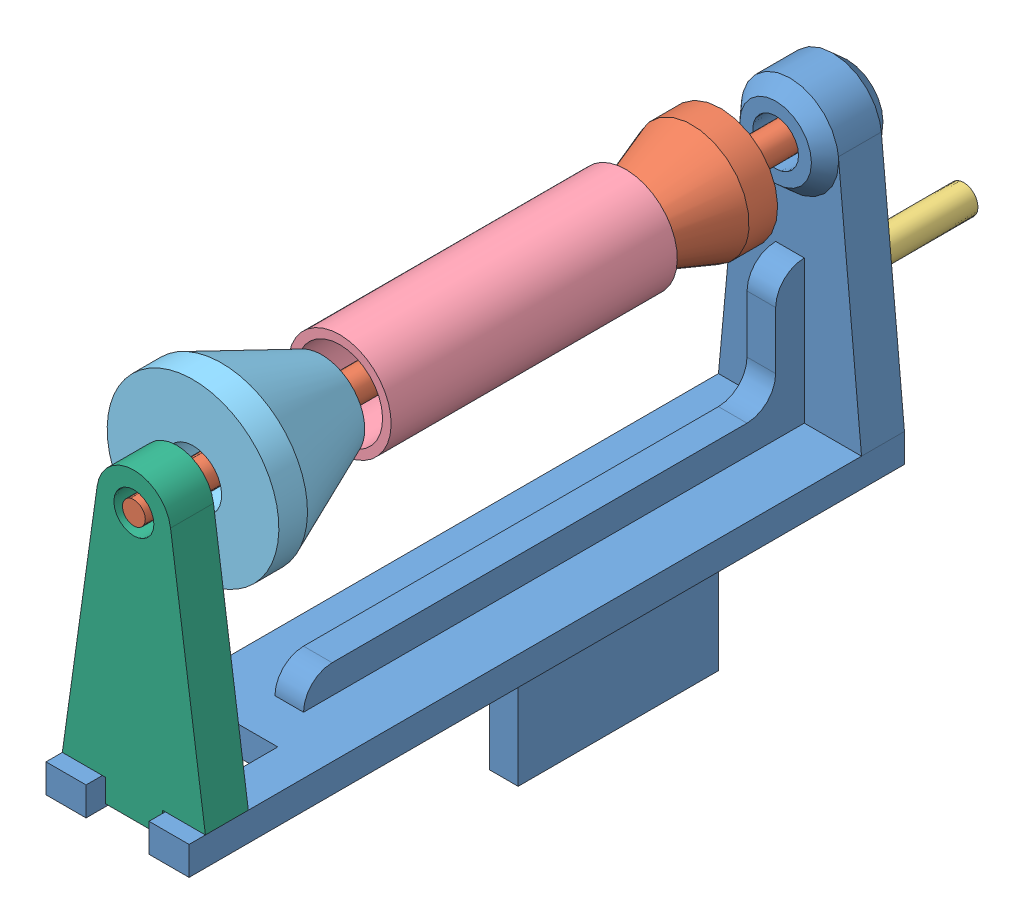
SolidWorks assembly Assem3, configuration Default. Lengths in mm.
Overall size (68.4 179.13 295.71).
6 component instances, 6 part files, 7 mates.
Components (placement in the parent):
- Part11-1: Part11 [Default] at origin size (50 161.93 255)
- spindle part-1: spindle part [Default] at (0 0 31.7929) x (0 0 -1) z (0.976249 -0.216652 0) size (250 40 40)
- spindle handle-1: spindle handle [Default] at (0 -25 -13.2071) size (18 68 47)
- coil former-1: coil former [Default] at (0 0 114.8801) x (0.979627 -0.200825 0) z (-0.200825 -0.979627 0) size (36 100 36)
- coil former locking-1: coil former locking [Default] at (0 0 193.6174) x (0 0 -1) z (0.988444 -0.151589 0) size (45 60 60)
- e nd-1: e nd [Default] at (0 0 229.2929) size (50 105.95 15)
Mates (geometry in assembly coordinates):
- Concentric2: concentric aligned: cylinder of Part11-1 through (0 0 1025) axis (0 0 1) radius 8; cylinder of spindle part-1 through (0 0 31.7929) axis (0 0 1) radius 3
- Concentric3: concentric anti-aligned: cylinder of spindle part-1 through (0 0 31.7929) axis (0 0 1) radius 3; cylinder of spindle handle-1 through (0 0 -6.2071) axis (0 0 -1) radius 3
- Coincident4: coincident aligned: plane of spindle part-1 through (0 0 -13.2071) normal (0 0 -1); plane of spindle handle-1 through (0 0 -13.2071) normal (0 0 -1)
- Concentric4: concentric anti-aligned: cylinder of spindle part-1 through (0 0 31.7929) axis (0 0 1) radius 5; cylinder of coil former-1 through (0 0 164.8801) axis (0 0 -1) radius 15
- Concentric5: concentric aligned: cylinder of spindle part-1 through (0 0 31.7929) axis (0 0 1) radius 4; cylinder of coil former locking-1 through (0 0 193.6174) axis (0 0 1) radius 10
- Concentric6: concentric anti-aligned: cylinder of spindle part-1 through (0 0 31.7929) axis (0 0 1) radius 4; cylinder of e nd-1 through (0 0 236.7929) axis (0 0 -1) radius 7
- Coincident9: coincident aligned: plane of e nd-1 through (0 0 229.2929) normal (1 0 0); plane of assembly
